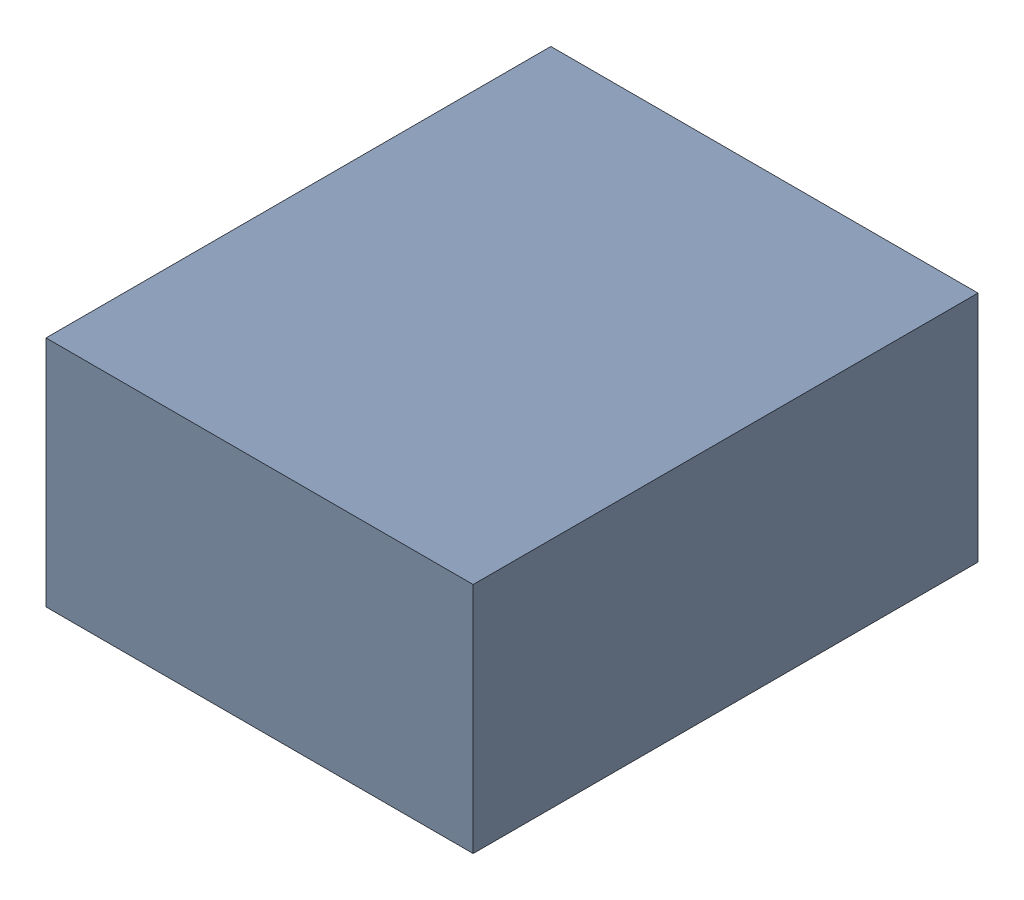
SolidWorks assembly C12, configuration Standard. Lengths in mm.
Overall size (1.1 0.6 1.3).
2 component instances, 1 part files, 0 mates.
Components (placement in the parent):
- 885542240-1: 885542240 [Standard] at (-22.06 -6.91 0) size (1.1 0.6 1.3)
  - Extruded_28-1: Extruded_28 [Standard] at origin size (1.1 0.6 1.3)
